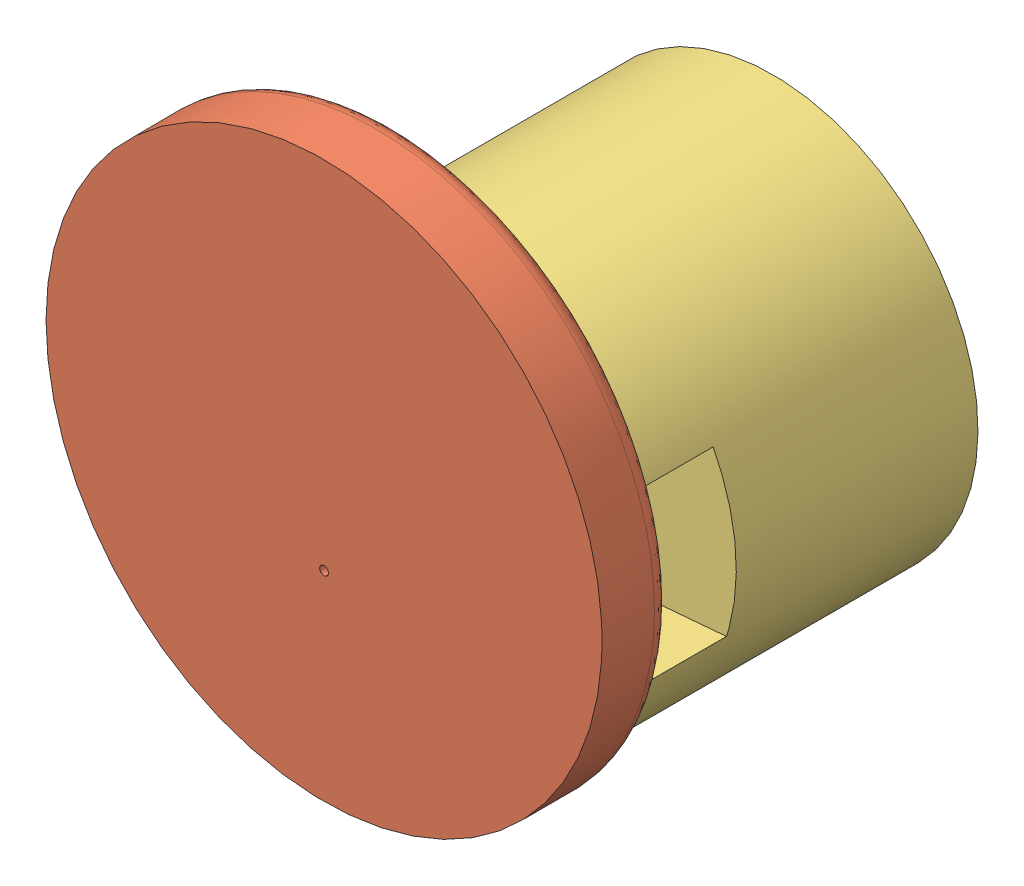
SolidWorks assembly LockAssembly, configuration Default. Lengths in mm.
Overall size (63.66 66.16 51.37).
4 component instances, 4 part files, 8 mates.
Components (placement in the parent):
- LockHandle-2: LockHandle [Default] at (18.7919 11.2979 36.5357) x (-0.084313 0.996439 0) z (0 0 1) size (14.33 49.76 14.81)
- LockBase-2: LockBase [Default] at (31.6258 -21.2536 38.4357) size (63.66 63.66 8)
- TwisterPiece-1: TwisterPiece [Default] at (31.6258 5.2046 36.5357) x (0.084313 -0.996439 0) z (0 0 -1) size (47 47 42.97)
- ServoHead-1: ServoHead [Default] at (31.6258 5.2046 1.8357) x (-0.084313 0.996439 0) z (0 0 1) size (41.5 43.5 6)
Mates (geometry in assembly coordinates):
- Concentric2: concentric aligned: cylinder of LockHandle-2 through (31.6258 5.2046 37.4357) axis (0 0 1) radius 0.5; cylinder of LockBase-2 through (31.6258 5.2046 38.4357) axis (0 0 1) radius 0.5
- Coincident6: coincident anti-aligned: plane of LockHandle-2 through (18.7919 11.2979 38.4357) normal (0 0 1); plane of LockBase-2 through (31.6258 14.1346 38.4357) normal (0 0 -1)
- Coincident9: coincident anti-aligned: plane of LockHandle-2 through (5.6586 3.0074 36.5357) normal (0 0 1); plane of TwisterPiece-1 through (31.6258 5.2046 36.5357) normal (0 0 -1)
- Concentric5: concentric anti-aligned: circle of LockHandle-2; circle of TwisterPiece-1
- Coincident15: coincident anti-aligned: plane of LockHandle-2 through (22.8518 11.6414 38.4357) normal (-0.996439 -0.084313 0); plane of TwisterPiece-1 through (24.218 -4.5046 36.5357) normal (0.996439 0.084313 0)
- Concentric10: concentric anti-aligned: circle of TwisterPiece-1; circle of ServoHead-1
- Concentric11: concentric anti-aligned: circle of TwisterPiece-1; circle of ServoHead-1
- Coincident22: coincident anti-aligned: plane of TwisterPiece-1 through (31.6258 5.2046 3.7357) normal (0 0 -1); plane of ServoHead-1 through (15.6827 3.8556 3.7357) normal (0 0 1)
